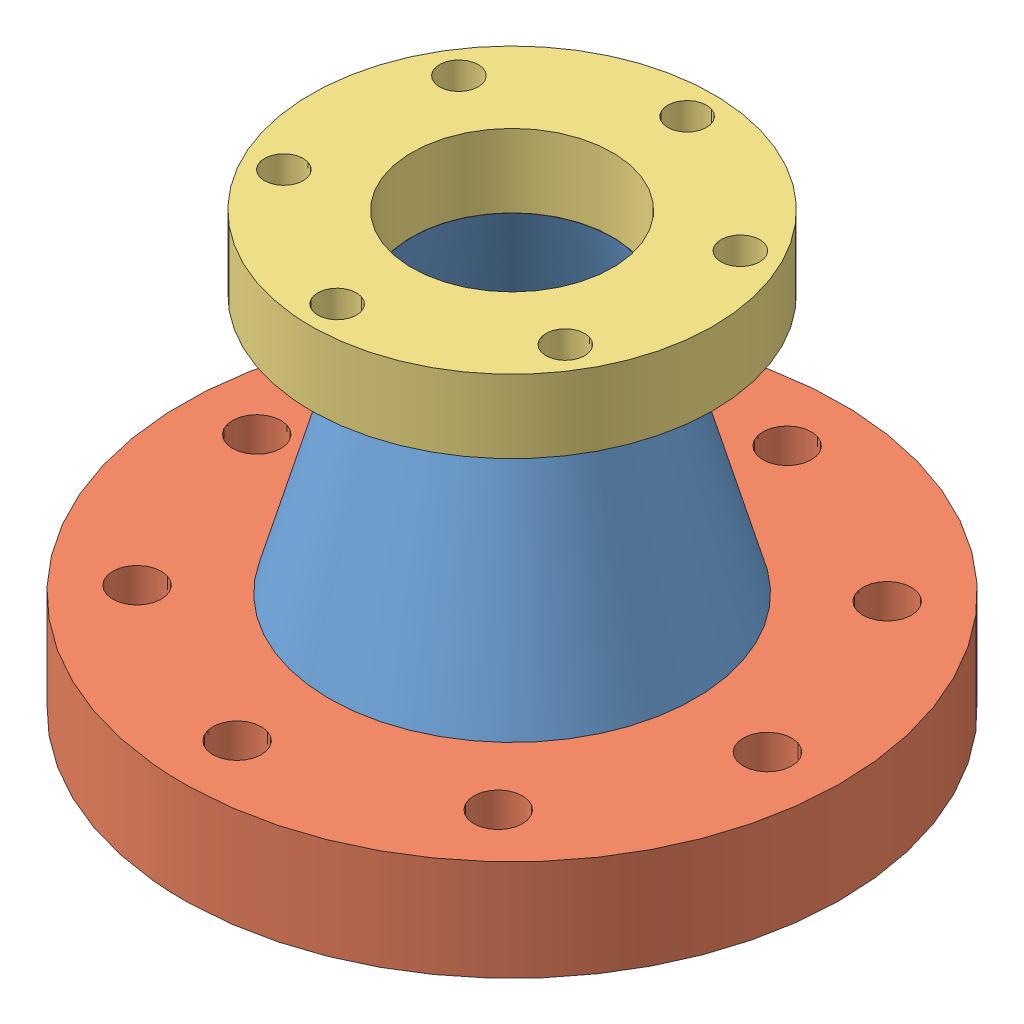
SolidWorks assembly 2.75-4.5in_reducer, configuration Default. Lengths in mm.
Overall size (118.45 75.16 118.45).
3 component instances, 3 part files, 6 mates.
Components (placement in the parent):
- 2.75-4.5in_reducer_tube-1: 2.75-4.5in_reducer_tube [Default] at (-9.1074 -19.0281 2.47) size (63.5 44.93 63.5)
- 4.5in_CF_flange-1: 4.5in_CF_flange [Default] at (-9.1074 -36.5541 2.47) x (0.999314 0 0.037029) z (-0.037029 0 0.999314) size (114.3 17.53 114.3)
- 2.75in_CF_flange-2: 2.75in_CF_flange [Default] at (-9.1074 25.9045 2.47) x (0.999314 0 0.037029) z (-0.037029 0 0.999314) size (69.85 12.7 69.85)
Mates (geometry in assembly coordinates):
- Concentric1: concentric aligned: circle of 2.75-4.5in_reducer_tube-1; circle of 4.5in_CF_flange-1
- Concentric2: concentric aligned: circle of 2.75-4.5in_reducer_tube-1; circle of 2.75in_CF_flange-2
- Concentric4: concentric aligned: circle of 2.75-4.5in_reducer_tube-1; circle of 2.75in_CF_flange-2
- Coincident1: coincident anti-aligned: plane of 2.75-4.5in_reducer_tube-1 through (-9.1074 25.9045 2.47) normal (0 1 0); plane of 2.75in_CF_flange-2
- Parallel1: parallel aligned: line of 4.5in_CF_flange-1 through (-9.1074 -36.5541 2.47) axis (0.037029 0 -0.999314); line of 2.75in_CF_flange-2 through (-9.1074 25.9045 2.47) axis (0.037029 0 -0.999314)
- Coincident2: coincident anti-aligned: plane of 2.75-4.5in_reducer_tube-1 through (-9.1074 -19.0281 2.47) normal (0 -1 0); plane of 4.5in_CF_flange-1 through (-9.1074 -19.0281 2.47) normal (0 1 0)
